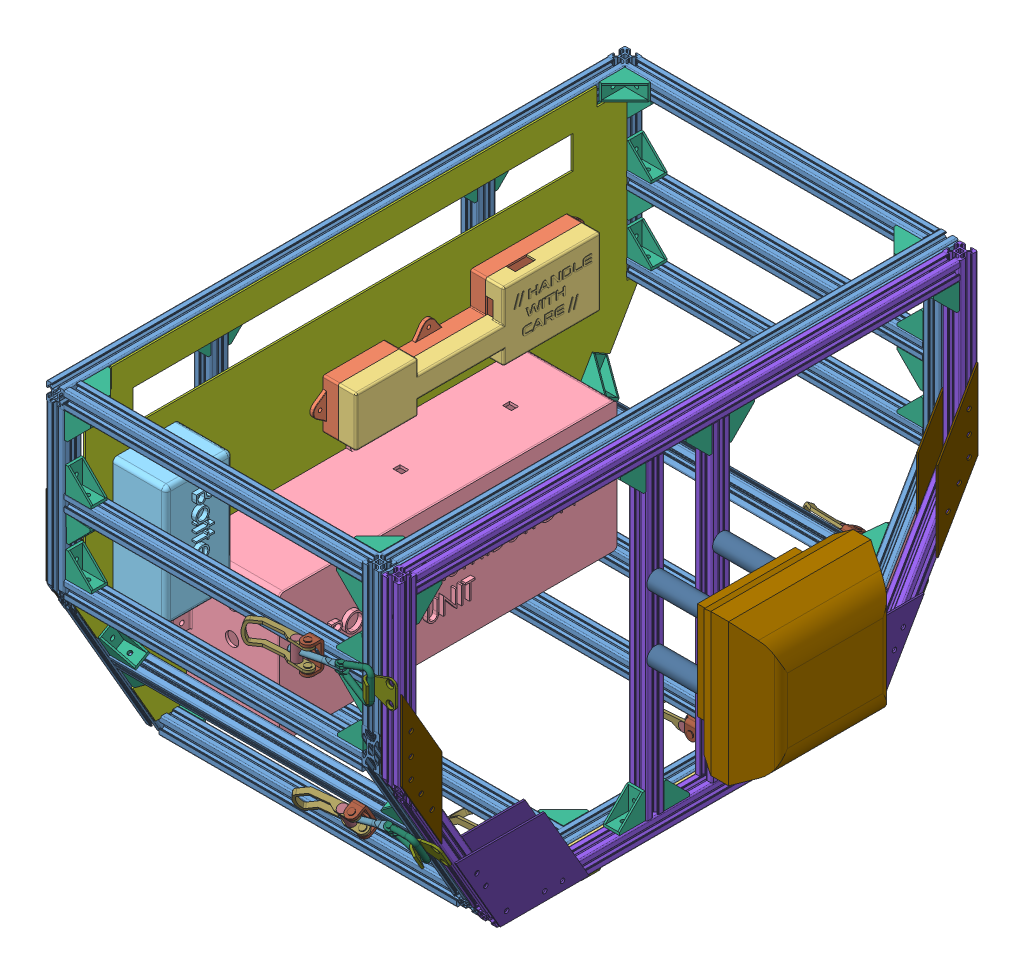
SolidWorks assembly EC, configuration Default. Lengths in mm.
Overall size (565.09 437.52 771.95).
126 component instances, 22 part files, 227 mates.
Components (placement in the parent):
- Electronics Compartment Chassis-1: Electronics Compartment Chassis [Default<As Machined>] at (390.9071 331.5 537.468) size (375 389.98 651)
- n_spartan_base-1: n_spartan_base [Default] at (47.906 291.3679 370.8745) x (0 0 -1) z (1 0 0) size (305.49 76.62 17)
- n_spartan_cover-1: n_spartan_cover [Default] at (82.906 343.2131 421.3662) x (0 0 -1) z (1 0 0) size (275.49 76.62 20.5)
- PDU Enclosure-1: PDU Enclosure [Default] at (50.906 216.04 537.5373) x (0 0 -1) z (1 0 0) size (420 186 110)
- Battery-2: Battery [Default] at (47.906 343.2622 772.8187) x (0 -1 0) z (1 0 0) size (135 75 65)
- L- Bracket-1: L- Bracket [Default] at (45.906 482.1078 853.4678) x (0 0 -1) z (-1 0 0) size (18 29 29)
- L- Bracket-2: L- Bracket [Default] at (45.906 491.6051 842.9695) x (0 1 0) z (-1 0 0) size (18 29 29)
- L- Bracket-3: L- Bracket [Default] at (36.4082 482.1065 842.9678) x (1 0 0) z (0 1 0) size (18 29 29)
- L- Bracket-4: L- Bracket [Default] at (380.9082 492.6078 842.9695) x (0 1 0) z (0 0 1) size (18 29 29)
- L- Bracket-5: L- Bracket [Default] at (390.406 482.1082 842.9695) x (1 0 0) z (0 1 0) size (18 29 29)
- L- Bracket-6: L- Bracket [Default] at (380.9082 482.1078 853.4695) x (0 0 -1) z (0 1 0) size (18 29 29)
- L- Bracket-7: L- Bracket [Default] at (45.906 482.1078 222.4695) x (0 0 -1) z (-1 0 0) size (18 29 29)
- L- Bracket-8: L- Bracket [Default] at (35.406 482.1065 231.9682) x (1 0 0) z (0 0 -1) size (18 29 29)
- L- Bracket-9: L- Bracket [Default] at (45.906 492.6065 231.9682) x (0 -1 0) z (-1 0 0) size (18 29 29)
- L- Bracket-10: L- Bracket [Default] at (380.9082 482.1078 222.4678) x (0 0 1) z (1 0 0) size (18 29 29)
- L- Bracket-11: L- Bracket [Default] at (380.9082 491.6069 231.9682) x (0 1 0) z (1 0 0) size (18 29 29)
- L- Bracket-12: L- Bracket [Default] at (391.4082 482.1082 231.9665) x (1 0 0) z (0 0 -1) size (18 29 29)
- L- Bracket-13: L- Bracket [Default] at (45.906 317.1056 852.4665) x (0 0 1) z (-1 0 0) size (18 29 29)
- L- Bracket-14: L- Bracket [Default] at (380.9082 317.1056 852.4682) x (0 0 -1) z (1 0 0) size (18 29 29)
- L- Bracket-15: L- Bracket [Default] at (380.9082 317.1056 222.4695) x (0 0 1) z (0 -1 0) size (18 29 29)
- L- Bracket-16: L- Bracket [Default] at (45.906 317.1056 222.4695) x (0 0 1) z (-1 0 0) size (18 29 29)
- L- Bracket-17: L- Bracket [Default] at (45.906 122.6252 736.1695) x (0 1 0) z (-1 0 0) size (18 29 29)
- L- Bracket-18: L- Bracket [Default] at (45.906 121.6239 338.7682) x (0 -1 0) z (-1 0 0) size (18 29 29)
- L- Bracket-20: L- Bracket [Default] at (380.9082 122.6234 338.7682) x (0 -1 0) z (0 0 -1) size (18 29 29)
- L- Bracket-21: L- Bracket [Default] at (380.9082 122.6234 736.1695) x (0 1 0) z (0 0 1) size (18 29 29)
- EC Bed-1: EC Bed [Default] at (47.906 -2.0799 1073.4615) x (0 -0.000568 1) z (-1 0 0) size (641.6 389.98 2)
- GPS Lid Assembly-1: GPS Lid Assembly [Default] at (101.4637 813.5756 803.4311) x (0 0 -1) z (-0.000003 -1 0) size (651 185.1 390)
  - GPS Lid-1: GPS Lid [Default<As Machined>] at (264.959 312.4365 321.65) size (651 20 390)
  - GPS-1: GPS [Default] at (220.0427 343.778 364.2591) size (160 165 160)
    - Electronics_GPS-1: Electronics_GPS [Default] at (45.0778 103.759 123.5701) size (160 100 160)
    - GPS_Spacer-1: GPS_Spacer [Default] at (82.0778 -21.241 160.5701) x (-0.327705 0 -0.94478) z (0 1 0) size (20 20 65)
    - GPS_Spacer-2: GPS_Spacer [Default] at (8.0778 -21.241 86.5701) x (0.991067 0 0.133362) z (0 1 0) size (20 20 65)
    - GPS_Spacer-3: GPS_Spacer [Default] at (8.0778 -21.241 160.5701) x (0.953346 0 0.301881) z (0 1 0) size (20 20 65)
    - GPS_Spacer-4: GPS_Spacer [Default] at (82.0778 -21.241 86.5701) x (0.550145 0 -0.835069) z (0 1 0) size (20 20 65)
  - L- Bracket-1: L- Bracket [Default] at (217.9605 311.9355 681.6515) x (0 -1 0) z (1 0 0) size (18 29 29)
  - L- Bracket-2: L- Bracket [Default] at (237.9592 312.9376 681.6515) x (0 1 0) z (-1 0 0) size (18 29 29)
  - L- Bracket-3: L- Bracket [Default] at (311.9592 312.9376 681.6515) x (0 1 0) z (-1 0 0) size (18 29 29)
  - L- Bracket-4: L- Bracket [Default] at (-40.5408 312.9376 331.6485) x (0 -1 0) z (-1 0 0) size (18 29 29)
  - L- Bracket-5: L- Bracket [Default] at (570.4605 312.9376 331.6485) x (0 1 0) z (1 0 0) size (18 29 29)
  - L- Bracket-6: L- Bracket [Default] at (311.9592 311.9355 331.6485) x (0 -1 0) z (-1 0 0) size (18 29 29)
  - L- Bracket-7: L- Bracket [Default] at (291.9605 312.9376 331.6485) x (0 1 0) z (1 0 0) size (18 29 29)
  - L- Bracket-8: L- Bracket [Default] at (217.9605 312.9376 331.6485) x (0 1 0) z (1 0 0) size (18 29 29)
- L- Bracket-22: L- Bracket [Default] at (45.906 213.29 276.7122) x (0 -0.5 -0.866025) z (0 -0.866025 0.5) size (18 29 29)
- L- Bracket-23: L- Bracket [Default] at (45.906 195.9711 286.7125) x (0 0.5 0.866025) z (0 0.866025 -0.5) size (18 29 29)
- L- Bracket-24: L- Bracket [Default] at (45.906 222.4898 803.5353) x (0 -0.5 0.866025) z (-1 0 0) size (18 29 29)
- L- Bracket-25: L- Bracket [Default] at (45.906 205.1704 793.536) x (0 0.5 -0.866025) z (-1 0 0) size (18 29 29)
- L- Bracket-26: L- Bracket [Default] at (45.906 122.6252 636.1695) x (0 1 0) z (-1 0 0) size (18 29 29)
- L- Bracket-27: L- Bracket [Default] at (45.906 122.6252 656.1682) x (0 -1 0) z (-1 0 0) size (18 29 29)
- ADJUSTABLE CLAMP-1: ADJUSTABLE CLAMP [LOCKED ] at (339.102 111.9247 428.703) x (0 0 -1) z (-0.000003 -1 0) size (39.54 155.02 32.17)
  - CLAMP - BRACKET-1: CLAMP - BRACKET [Default] at origin size (33.5 16 18)
  - CLAMP - HANDLE-1: CLAMP - HANDLE [Default] at origin size (25.5 70.98 19.58)
  - SWIVEL PIN-1: SWIVEL PIN [Default] at (0 -3.0558 -3.8626) x (1 0 0) z (0 0.221472 0.975167) size (25 10 10)
  - ADJUSTMENT SCREW-1: ADJUSTMENT SCREW [Default] at (0 6.7802 -6.2479) x (1 0 0) z (0 0.221472 0.975167) size (7.24 54.03 12.85)
  - LATCH-1: LATCH [Default] at (0 12.0699 -12.0483) x (1 0 0) z (0 -0.243377 0.969932) size (39.54 46.19 13.29)
  - CATCH-1: CATCH [Default] at (0 9 0) size (30 30.4 16.71)
- ADJUSTABLE CLAMP-2: ADJUSTABLE CLAMP [LOCKED ] at (339.102 111.9247 646.6324) x (0 0 -1) z (-0.000003 -1 0) size (39.54 155.02 32.17)
  - CLAMP - BRACKET-1: CLAMP - BRACKET [Default] at origin size (33.5 16 18)
  - CLAMP - HANDLE-1: CLAMP - HANDLE [Default] at origin size (25.5 70.98 19.58)
  - SWIVEL PIN-1: SWIVEL PIN [Default] at (0 -3.0558 -3.8626) x (1 0 0) z (0 0.221472 0.975167) size (25 10 10)
  - ADJUSTMENT SCREW-1: ADJUSTMENT SCREW [Default] at (0 6.7802 -6.2479) x (1 0 0) z (0 0.221472 0.975167) size (7.24 54.03 12.85)
  - LATCH-1: LATCH [Default] at (0 12.0699 -12.0483) x (1 0 0) z (0 -0.243377 0.969932) size (39.54 46.19 13.29)
  - CATCH-1: CATCH [Default] at (0 9 0) size (30 30.4 16.71)
- ADJUSTABLE CLAMP-3: ADJUSTABLE CLAMP [LOCKED ] at (339.1022 207.7726 808.2717) x (-0.000002 -0.866025 -0.5) z (-0.000001 -0.5 0.866025) size (39.54 155.02 32.17)
  - CLAMP - BRACKET-1: CLAMP - BRACKET [Default] at origin size (33.5 16 18)
  - CLAMP - HANDLE-1: CLAMP - HANDLE [Default] at origin size (25.5 70.98 19.58)
  - SWIVEL PIN-1: SWIVEL PIN [Default] at (0 -3.0558 -3.8626) x (1 0 0) z (0 0.221472 0.975167) size (25 10 10)
  - ADJUSTMENT SCREW-1: ADJUSTMENT SCREW [Default] at (0 6.7802 -6.2479) x (1 0 0) z (0 0.221472 0.975167) size (7.24 54.03 12.85)
  - LATCH-1: LATCH [Default] at (0 12.0699 -12.0483) x (1 0 0) z (0 -0.243377 0.969932) size (39.54 46.19 13.29)
  - CATCH-1: CATCH [Default] at (0 9 0) size (30 30.4 16.71)
- L- Bracket-28: L- Bracket [Default] at (45.906 122.6252 418.7695) x (0 1 0) z (-1 0 0) size (18 29 29)
- L- Bracket-29: L- Bracket [Default] at (45.906 122.6252 438.7682) x (0 -1 0) z (-1 0 0) size (18 29 29)
- L- Bracket-30: L- Bracket [Default] at (45.906 381.9702 221.4682) x (0 0 1) z (0 1 0) size (18 29 29)
- L- Bracket-31: L- Bracket [Default] at (45.906 401.9689 222.4695) x (0 0 1) z (-1 0 0) size (18 29 29)
- L- Bracket-33: L- Bracket [Default] at (48.0128 401.8743 854.7029) x (-0.002846 -0.000008 0.999996) z (-0.999992 -0.002846 -0.002847) size (18 29 29)
- L- Bracket-34: L- Bracket [Default] at (47.2341 381.8733 852.424) x (-0.070876 -0.000202 0.997485) z (-0.002847 0.999996 0) size (18 29 29)
- L- Bracket-35: L- Bracket [Default] at (380.9082 401.9689 222.4678) x (0 0 1) z (0 -1 0) size (18 29 29)
- L- Bracket-36: L- Bracket [Default] at (380.9082 381.9702 222.4678) x (0 0 -1) z (0 1 0) size (18 29 29)
- L- Bracket-37: L- Bracket [Default] at (380.9082 213.2891 276.7107) x (0 0.5 0.866025) z (0 -0.866025 0.5) size (18 29 29)
- L- Bracket-38: L- Bracket [Default] at (380.9082 195.9697 286.71) x (0 -0.5 -0.866025) z (0 0.866025 -0.5) size (18 29 29)
- L- Bracket-39: L- Bracket [Default] at (380.9082 122.6234 418.7695) x (0 1 0) z (0 0 1) size (18 29 29)
- L- Bracket-40: L- Bracket [Default] at (380.9082 122.6234 438.7682) x (0 -1 0) z (0 0 -1) size (18 29 29)
- L- Bracket-41: L- Bracket [Default] at (380.9082 122.6234 656.1682) x (0 -1 0) z (0 0 -1) size (18 29 29)
- L- Bracket-42: L- Bracket [Default] at (380.9082 122.6234 636.1695) x (0 1 0) z (0 0 1) size (18 29 29)
- L- Bracket-43: L- Bracket [Default] at (380.9082 205.1695 793.5375) x (0 0.5 -0.866025) z (0 0.866025 0.5) size (18 29 29)
- L- Bracket-44: L- Bracket [Default] at (380.9082 222.4889 803.5368) x (0 -0.5 0.866025) z (0 -0.866025 -0.5) size (18 29 29)
- L- Bracket-45: L- Bracket [Default] at (380.9082 382.851 852.453) x (0 -0.006101 0.999981) z (1 0 0) size (18 29 29)
- L- Bracket-46: L- Bracket [Default] at (380.9082 403.0563 853.4359) x (0 0.003337 -0.999994) z (1 0 0) size (18 29 29)
- ADJUSTABLE CLAMP-4: ADJUSTABLE CLAMP [LOCKED ] at (339.1022 199.1283 273.6613) x (0.000002 0.866025 -0.5) z (-0.000001 -0.5 -0.866025) size (39.54 155.02 32.17)
  - CLAMP - BRACKET-1: CLAMP - BRACKET [Default] at origin size (33.5 16 18)
  - CLAMP - HANDLE-1: CLAMP - HANDLE [Default] at origin size (25.5 70.98 19.58)
  - SWIVEL PIN-1: SWIVEL PIN [Default] at (0 -3.0558 -3.8626) x (1 0 0) z (0 0.221472 0.975167) size (25 10 10)
  - ADJUSTMENT SCREW-1: ADJUSTMENT SCREW [Default] at (0 6.7802 -6.2479) x (1 0 0) z (0 0.221472 0.975167) size (7.24 54.03 12.85)
  - LATCH-1: LATCH [Default] at (0 12.0699 -12.0483) x (1 0 0) z (0 -0.243377 0.969932) size (39.54 46.19 13.29)
  - CATCH-1: CATCH [Default] at (0 9 0) size (30 30.4 16.71)
- ADJUSTABLE CLAMP-7: ADJUSTABLE CLAMP [LOCKED ] at (339.1027 392.0581 863.9706) x (-0.000003 -1 0) z (0 0 1) size (39.54 155.02 32.17)
  - CLAMP - BRACKET-1: CLAMP - BRACKET [Default] at origin size (33.5 16 18)
  - CLAMP - HANDLE-1: CLAMP - HANDLE [Default] at origin size (25.5 70.98 19.58)
  - SWIVEL PIN-1: SWIVEL PIN [Default] at (0 -3.0558 -3.8626) x (1 0 0) z (0 0.221472 0.975167) size (25 10 10)
  - ADJUSTMENT SCREW-1: ADJUSTMENT SCREW [Default] at (0 6.7802 -6.2479) x (1 0 0) z (0 0.221472 0.975167) size (7.24 54.03 12.85)
  - LATCH-1: LATCH [Default] at (0 12.0699 -12.0483) x (1 0 0) z (0 -0.243377 0.969932) size (39.54 46.19 13.29)
  - CATCH-1: CATCH [Default] at (0 9 0) size (30 30.4 16.71)
- EC Shear Plate 1-1: EC Shear Plate 1 [Default] at (402.906 200.226 801.0756) x (0 -0.153016 -0.988224) z (-1 0 0) size (161.49 93.23 2)
- EC Shear Plate 1-2: EC Shear Plate 1 [Default] at (402.906 113.6234 423.8604) x (0 0.779319 -0.626628) z (-1 0 0) size (161.49 93.23 2)
- EC Shear Plate 2-1: EC Shear Plate 2 [Default] at (402.906 226.8868 816.4682) x (0 0.707107 0.707107) z (-1 0 0) size (150.57 86.93 2)
- EC Shear Plate 2-2: EC Shear Plate 2 [Default] at (400.906 226.8868 258.4678) x (0 0.707107 -0.707107) z (1 0 0) size (150.57 86.93 2)
- EC Shear Plate 1-3: EC Shear Plate 1 [Default] at (25.9082 113.6252 423.8614) x (0 0.779319 -0.626628) z (-1 0 0) size (161.49 93.23 2)
- EC Shear Plate 1-4: EC Shear Plate 1 [Default] at (25.9082 200.2277 801.0746) x (0 -0.153016 -0.988224) z (-1 0 0) size (161.49 93.23 2)
- EC Shear Plate 2-3: EC Shear Plate 2 [Default] at (23.9082 226.8872 258.4695) x (0 0.707107 -0.707107) z (1 0 0) size (150.57 86.93 2)
- EC Shear Plate 2-4: EC Shear Plate 2 [Default] at (23.9082 394.8295 861.4665) x (0 -0.965926 0.258819) z (1 0 0) size (150.57 86.93 2)
- EC Shear Plate 1-5: EC Shear Plate 1 [Default] at (425.8975 200.027 802.0679) x (0 -0.153016 -0.988224) z (-1 0.000003 0) size (161.49 93.23 2)
- EC Shear Plate 1-6: EC Shear Plate 1 [Default] at (425.8972 113.4245 424.8743) x (0.000002 0.779319 -0.626628) z (-1 0.000003 0) size (161.49 93.23 2)
- EC Shear Plate 2-5: EC Shear Plate 2 [Default] at (423.8975 226.7048 259.4719) x (0.000002 0.707107 -0.707107) z (1 -0.000003 0) size (150.57 86.93 2)
- EC Shear Plate 2-6: EC Shear Plate 2 [Default] at (425.8975 226.7053 817.4706) x (0.000002 0.707107 0.707107) z (-1 0.000003 0) size (150.57 86.93 2)
- EC Spacer 1-1: EC Spacer 1 [Default] at (403.906 0 1074.936) x (0 0 1) z (-1 0 0) size (648 134.82 3)
- EC Spacer 3-1: EC Spacer 3 [Default] at (400.906 -0.0558 -0.0322) x (0 0 -1) z (1 0 0) size (34.53 59.81 3)
- EC Spacer 2-1: EC Spacer 2 [Default] at (403.906 0 1075.3966) x (0 0 1) z (-1 0 0) size (244.81 17 3)
- EC Spacer 4-1: EC Spacer 4 [Default] at (436.1631 0.8411 1.5304) x (0.093475 0.00253 -0.995618) z (0.994158 0.053968 0.093475) size (34.65 60.01 3)
- L- Bracket-47: L- Bracket [Default] at (36.4093 482.1065 397.4682) x (1 0 0) z (0 0 -1) size (18 29 29)
- L- Bracket-48: L- Bracket [Default] at (36.4082 482.1065 377.4695) x (1 0 0) z (0 1 0) size (18 29 29)
- L- Bracket-49: L- Bracket [Default] at (36.4082 482.1065 677.4695) x (-1 0 0) z (0 0 1) size (18 29 29)
- L- Bracket-50: L- Bracket [Default] at (45.906 401.9689 222.4695) x (0 0 1) z (-1 0 0) size (18 29 29)
- L- Bracket-51: L- Bracket [Default] at (36.4082 482.1065 697.4682) x (1 0 0) z (0 0 -1) size (18 29 29)
- L- Bracket-52: L- Bracket [Default] at (36.4082 132.1239 377.4695) size (18 29 29)
- L- Bracket-53: L- Bracket [Default] at (36.4082 132.1239 397.4682) x (-1 0 0) z (0 0 -1) size (18 29 29)
- L- Bracket-54: L- Bracket [Default] at (36.4082 132.1239 677.4695) size (18 29 29)
- L- Bracket-55: L- Bracket [Default] at (36.4082 132.1239 697.4682) x (-1 0 0) z (0 0 -1) size (18 29 29)
Mates (geometry in assembly coordinates):
- Coincident183: coincident: plane of Electronics Compartment Chassis-1 through (47.906 331.5 537.468) normal (1 0 0); plane of n_spartan_base-1 through (47.906 291.3679 370.8745) normal (-1 0 0)
- Lock9: lock: unknown of Electronics Compartment Chassis-1; unknown of n_spartan_base-1
- Coincident185: coincident: line of n_spartan_base-1 through (64.906 391.3411 298.0369) axis (0 -1 0); line of n_spartan_cover-1 through (64.906 318.7182 298.0369) axis (0 1 0)
- Coincident186: coincident: line of n_spartan_base-1 through (64.906 332.8683 408.5193) axis (0 0 1); line of n_spartan_cover-1 through (64.906 332.8683 502.5227) axis (0 0 -1)
- Coincident187: coincident: plane of Electronics Compartment Chassis-1 through (47.906 331.5 537.468) normal (1 0 0); plane of PDU Enclosure-1 through (47.906 216.04 537.5373) normal (-1 0 0)
- Lock12: lock: unknown of Electronics Compartment Chassis-1; unknown of PDU Enclosure-1
- Coincident192: coincident: plane of Electronics Compartment Chassis-1 through (47.906 331.5 537.468) normal (1 0 0); plane of Battery-2 through (47.906 343.2622 772.8187) normal (-1 0 0)
- Parallel7: parallel: line of Electronics Compartment Chassis-1 through (47.906 480.6069 861.4682) axis (0 -1 0); line of Battery-2 through (47.906 405.7622 810.3187) axis (0 -1 0)
- Coincident280389272: coincident: plane of Electronics Compartment Chassis-1 through (45.906 307.1067 856.7169) normal (1 0 0); plane of L- Bracket-1 through (45.906 453.1078 862.4678) normal (-1 0 0)
- Coincident280389273: coincident: plane of Electronics Compartment Chassis-1 through (35.9071 482.1078 856.7169) normal (0 -1 0); plane of L- Bracket-1 through (45.906 482.1078 862.4678) normal (0 1 0)
- Coincident280389274: coincident: line of Electronics Compartment Chassis-1 through (45.906 272.3869 844.4678) axis (0 1 0); line of L- Bracket-1 through (45.906 453.1078 844.4678) axis (0 1 0)
- Coincident280389275: coincident: plane of Electronics Compartment Chassis-1 through (45.906 495.8556 852.968) normal (1 0 0); plane of L- Bracket-2 through (45.906 482.6051 813.9695) normal (-1 0 0)
- Coincident280389276: coincident: plane of Electronics Compartment Chassis-1 through (35.9071 500.6056 842.9695) normal (0 0 -1); plane of L- Bracket-2 through (45.906 482.6051 842.9695) normal (0 0 1)
- Coincident280389277: coincident: line of Electronics Compartment Chassis-1 through (45.906 500.6051 862.9665) axis (0 0 -1); line of L- Bracket-2 through (45.906 500.6051 813.9695) axis (0 0 1)
- Coincident280389278: coincident: plane of Electronics Compartment Chassis-1 through (27.4082 482.1065 852.968) normal (0 -1 0); plane of L- Bracket-3 through (27.4082 482.1065 813.9678) normal (0 1 0)
- Coincident280389279: coincident: plane of Electronics Compartment Chassis-1 through (39.656 307.1067 842.9678) normal (0 0 -1); plane of L- Bracket-3 through (27.4082 482.1065 842.9678) normal (0 0 1)
- Coincident280389280: coincident: line of Electronics Compartment Chassis-1 through (27.4082 269.7889 842.9678) axis (0 1 0); line of L- Bracket-3 through (27.4082 482.1065 842.9678) axis (0 -1 0)
- Coincident280389281: coincident: plane of Electronics Compartment Chassis-1 through (380.9082 495.8556 221.968) normal (-1 0 0); plane of L- Bracket-4 through (380.9082 483.6078 842.9695) normal (1 0 0)
- Coincident280389282: coincident: plane of Electronics Compartment Chassis-1 through (35.9071 500.6056 842.9695) normal (0 0 -1); plane of L- Bracket-4 through (351.9082 483.6078 842.9695) normal (0 0 1)
- Coincident280389283: coincident: line of Electronics Compartment Chassis-1 through (45.906 483.6078 842.9695) axis (1 0 0); line of L- Bracket-4 through (351.9082 483.6078 842.9695) axis (1 0 0)
- Coincident280389284: coincident: plane of Electronics Compartment Chassis-1 through (399.406 492.1067 842.9695) normal (0 0 -1); plane of L- Bracket-5 through (381.406 482.1082 842.9695) normal (0 0 1)
- Coincident280389285: coincident: plane of Electronics Compartment Chassis-1 through (399.406 482.1082 221.968) normal (0 -1 0); plane of L- Bracket-5 through (381.406 482.1082 813.9695) normal (0 1 0)
- Coincident280389286: coincident: line of Electronics Compartment Chassis-1 through (399.406 502.1069 842.9695) axis (0 -1 0); line of L- Bracket-5 through (399.406 482.1082 842.9695) axis (0 -1 0)
- Coincident280389287: coincident: plane of Electronics Compartment Chassis-1 through (35.9071 482.1078 844.4695) normal (0 -1 0); plane of L- Bracket-6 through (351.9082 482.1078 862.4695) normal (0 1 0)
- Coincident280389288: coincident: plane of Electronics Compartment Chassis-1 through (380.9082 492.1067 856.7169) normal (-1 0 0); plane of L- Bracket-6 through (380.9082 482.1078 862.4695) normal (1 0 0)
- Coincident280389289: coincident: line of Electronics Compartment Chassis-1 through (380.9082 502.1069 844.4695) axis (0 -1 0); line of L- Bracket-6 through (380.9082 482.1078 844.4695) axis (0 -1 0)
- Coincident280389290: coincident: plane of Electronics Compartment Chassis-1 through (35.9071 482.1078 213.4695) normal (0 -1 0); plane of L- Bracket-7 through (45.906 482.1078 231.4695) normal (0 1 0)
- Coincident280389291: coincident: plane of Electronics Compartment Chassis-1 through (45.906 492.1067 218.2191) normal (1 0 0); plane of L- Bracket-7 through (45.906 453.1078 231.4695) normal (-1 0 0)
- Coincident280389292: coincident: line of Electronics Compartment Chassis-1 through (45.906 502.1051 213.4695) axis (0 -1 0); line of L- Bracket-7 through (45.906 453.1078 213.4695) axis (0 1 0)
- Coincident280389293: coincident: plane of Electronics Compartment Chassis-1 through (39.656 482.1065 852.968) normal (0 -1 0); plane of L- Bracket-8 through (26.406 482.1065 231.9682) normal (0 1 0)
- Coincident280389294: coincident: plane of Electronics Compartment Chassis-1 through (27.4082 492.1067 231.9682) normal (0 0 1); plane of L- Bracket-8 through (26.406 453.1065 231.9682) normal (0 0 -1)
- Coincident280389295: coincident: line of Electronics Compartment Chassis-1 through (44.406 482.1065 862.9665) axis (0 0 -1); line of L- Bracket-8 through (44.406 482.1065 231.9682) axis (0 0 1)
- Coincident280389296: coincident: plane of Electronics Compartment Chassis-1 through (35.9071 495.8556 231.9682) normal (0 0 1); plane of L- Bracket-9 through (45.906 501.6065 231.9682) normal (0 0 -1)
- Coincident280389297: coincident: plane of Electronics Compartment Chassis-1 through (45.906 495.8556 852.968) normal (1 0 0); plane of L- Bracket-9 through (45.906 501.6065 260.9682) normal (-1 0 0)
- Coincident280389298: coincident: line of Electronics Compartment Chassis-1 through (45.906 483.6065 862.9665) axis (0 0 -1); line of L- Bracket-9 through (45.906 483.6065 260.9682) axis (0 0 -1)
- Coincident280389299: coincident: plane of Electronics Compartment Chassis-1 through (380.9082 307.1067 230.4665) normal (-1 0 0); plane of L- Bracket-10 through (380.9082 453.1078 213.4678) normal (1 0 0)
- Coincident280389300: coincident: plane of Electronics Compartment Chassis-1 through (35.9071 482.1078 213.4695) normal (0 -1 0); plane of L- Bracket-10 through (380.9082 482.1078 213.4678) normal (0 1 0)
- Coincident280389301: coincident: line of Electronics Compartment Chassis-1 through (380.9082 301.8291 213.4678) axis (0 1 0); line of L- Bracket-10 through (380.9082 453.1078 213.4678) axis (0 1 0)
- Coincident280389302: coincident: plane of Electronics Compartment Chassis-1 through (380.9082 483.6082 221.968) normal (-1 0 0); plane of L- Bracket-11 through (380.9082 482.6069 260.9682) normal (1 0 0)
- Coincident280389303: coincident: plane of Electronics Compartment Chassis-1 through (35.9071 495.8556 231.9682) normal (0 0 1); plane of L- Bracket-11 through (380.9082 482.6069 231.9682) normal (0 0 -1)
- Coincident280389304: coincident: line of Electronics Compartment Chassis-1 through (380.9082 500.6069 211.9678) axis (0 0 1); line of L- Bracket-11 through (380.9082 500.6069 260.9682) axis (0 0 -1)
- Coincident280389305: coincident: plane of Electronics Compartment Chassis-1 through (399.406 482.1082 221.968) normal (0 -1 0); plane of L- Bracket-12 through (382.4082 482.1082 231.9665) normal (0 1 0)
- Coincident280389306: coincident: plane of Electronics Compartment Chassis-1 through (387.1582 307.1067 231.9665) normal (0 0 1); plane of L- Bracket-12 through (382.4082 453.1082 231.9665) normal (0 0 -1)
- Coincident280389307: coincident: line of Electronics Compartment Chassis-1 through (382.4082 269.7884 231.9665) axis (0 1 0); line of L- Bracket-12 through (382.4082 453.1082 231.9665) axis (0 1 0)
- Coincident280389308: coincident: plane of Electronics Compartment Chassis-1 through (35.9071 317.1056 861.4682) normal (0 1 0); plane of L- Bracket-13 through (45.906 317.1056 843.4665) normal (0 -1 0)
- Coincident280389309: coincident: plane of Electronics Compartment Chassis-1 through (45.906 307.1067 856.7169) normal (1 0 0); plane of L- Bracket-13 through (45.906 346.1056 843.4665) normal (-1 0 0)
- Coincident280389310: coincident: line of Electronics Compartment Chassis-1 through (45.906 301.8295 861.4665) axis (0 1 0); line of L- Bracket-13 through (45.906 346.1056 861.4665) axis (0 -1 0)
- Coincident280389311: coincident: plane of L- Bracket-14 through (380.9082 346.1056 861.4682) normal (1 0 0); plane of Electronics Compartment Chassis-1 through (380.9082 492.1067 856.7169) normal (-1 0 0)
- Coincident280389312: coincident: line of Electronics Compartment Chassis-1 through (45.906 317.1056 861.4682) axis (1 0 0); line of L- Bracket-14 through (380.9082 317.1056 861.4682) axis (-1 0 0)
- Coincident280389313: coincident: plane of Electronics Compartment Chassis-1 through (35.9071 317.1056 230.4682) normal (0 1 0); plane of L- Bracket-15 through (351.9082 317.1056 213.4695) normal (0 -1 0)
- Coincident280389314: coincident: plane of Electronics Compartment Chassis-1 through (380.9082 307.1067 218.2191) normal (-1 0 0); plane of L- Bracket-15 through (380.9082 317.1056 213.4695) normal (1 0 0)
- Coincident280389315: coincident: line of Electronics Compartment Chassis-1 through (45.906 317.1056 213.4695) axis (1 0 0); line of L- Bracket-15 through (351.9082 317.1056 213.4695) axis (1 0 0)
- Coincident280389316: coincident: plane of Electronics Compartment Chassis-1 through (35.9071 317.1056 218.2191) normal (0 1 0); plane of L- Bracket-16 through (45.906 317.1056 213.4695) normal (0 -1 0)
- Coincident280389317: coincident: plane of Electronics Compartment Chassis-1 through (45.906 492.1067 230.4682) normal (1 0 0); plane of L- Bracket-16 through (45.906 346.1056 213.4695) normal (-1 0 0)
- Coincident280389318: coincident: line of Electronics Compartment Chassis-1 through (45.906 502.1051 213.4695) axis (0 -1 0); line of L- Bracket-16 through (45.906 346.1056 213.4695) axis (0 -1 0)
- Coincident280389319: coincident: plane of Electronics Compartment Chassis-1 through (45.906 118.3747 328.768) normal (1 0 0); plane of L- Bracket-17 through (45.906 113.6252 707.1695) normal (-1 0 0)
- Coincident280389320: coincident: plane of Electronics Compartment Chassis-1 through (35.9071 130.6226 736.1695) normal (0 0 -1); plane of L- Bracket-17 through (45.906 113.6252 736.1695) normal (0 0 1)
- Coincident280389321: coincident: line of Electronics Compartment Chassis-1 through (45.906 113.6252 322.1294) axis (0 0 1); line of L- Bracket-17 through (45.906 113.6252 707.1695) axis (0 0 1)
- Coincident280389322: coincident: plane of Electronics Compartment Chassis-1 through (45.906 130.6239 328.768) normal (1 0 0); plane of L- Bracket-18 through (45.906 130.6239 367.7682) normal (-1 0 0)
- Coincident280389323: coincident: plane of Electronics Compartment Chassis-1 through (35.9071 113.6248 338.7682) normal (0 0 1); plane of L- Bracket-18 through (45.906 130.6239 338.7682) normal (0 0 -1)
- Coincident280389324: coincident: line of Electronics Compartment Chassis-1 through (45.906 130.6239 312.3152) axis (0 0 1); line of L- Bracket-18 through (45.906 130.6239 367.7682) axis (0 0 -1)
- Coincident280389328: coincident: plane of Electronics Compartment Chassis-1 through (35.9071 125.8726 338.7682) normal (0 0 1); plane of L- Bracket-20 through (351.9082 131.6234 338.7682) normal (0 0 -1)
- Coincident280389329: coincident: plane of Electronics Compartment Chassis-1 through (380.9082 130.6221 746.168) normal (-1 0 0); plane of L- Bracket-20 through (380.9082 131.6234 338.7682) normal (1 0 0)
- Coincident280389330: coincident: line of Electronics Compartment Chassis-1 through (380.9082 113.6234 752.8077) axis (0 0 -1); line of L- Bracket-20 through (380.9082 113.6234 338.7682) axis (0 0 1)
- Coincident280389331: coincident: plane of Electronics Compartment Chassis-1 through (380.9082 130.6221 746.168) normal (-1 0 0); plane of L- Bracket-21 through (380.9082 113.6234 736.1695) normal (1 0 0)
- Coincident280389332: coincident: plane of Electronics Compartment Chassis-1 through (35.9071 118.3747 736.1695) normal (0 0 -1); plane of L- Bracket-21 through (351.9082 113.6234 736.1695) normal (0 0 1)
- Coincident280389333: coincident: line of Electronics Compartment Chassis-1 through (380.9082 113.6234 752.8077) axis (0 0 -1); line of L- Bracket-21 through (380.9082 113.6234 736.1695) axis (0 0 -1)
- Coincident280389334: coincident: plane of Electronics Compartment Chassis-1 through (45.906 495.8556 852.968) normal (1 0 0); plane of EC Bed-1 through (45.906 -2.0799 1073.4615) normal (-1 0 0)
- Lock21: lock: unknown of Electronics Compartment Chassis-1; unknown of EC Bed-1
- Coincident280389336: coincident: plane of Electronics Compartment Chassis-1 through (45.906 305.2322 218.7213) normal (1 0 0); plane of L- Bracket-22 through (45.906 217.79 284.5064) normal (-1 0 0)
- Coincident280389337: coincident: plane of Electronics Compartment Chassis-1 through (45.906 211.1655 273.0325) normal (0 0.866025 -0.5); plane of L- Bracket-22 through (74.906 217.79 284.5064) normal (0 -0.866025 0.5)
- Coincident280389338: coincident: line of Electronics Compartment Chassis-1 through (45.906 307.4276 211.9695) axis (0 -0.866025 0.5); line of L- Bracket-22 through (45.906 208.79 268.918) axis (0 0.866025 -0.5)
- Coincident280389339: coincident: plane of Electronics Compartment Chassis-1 through (45.906 197.5951 289.5252) normal (0 -0.866025 0.5); plane of L- Bracket-23 through (74.906 191.4711 278.9183) normal (0 0.866025 -0.5)
- Coincident280389340: coincident: plane of Electronics Compartment Chassis-1 through (45.906 305.2322 218.7213) normal (1 0 0); plane of L- Bracket-23 through (45.906 191.4711 278.9183) normal (-1 0 0)
- Coincident280389341: coincident: line of Electronics Compartment Chassis-1 through (45.906 191.4711 278.9183) axis (1 0 0); line of L- Bracket-23 through (74.906 191.4711 278.9183) axis (-1 0 0)
- Coincident280389342: coincident: plane of Electronics Compartment Chassis-1 through (380.9082 220.3653 807.215) normal (0 0.866025 0.5); plane of L- Bracket-24 through (45.906 226.9898 795.7411) normal (0 -0.866025 -0.5)
- Coincident280389343: coincident: plane of Electronics Compartment Chassis-1 through (45.906 120.2492 749.4147) normal (1 0 0); plane of L- Bracket-24 through (45.906 252.1045 810.2411) normal (-1 0 0)
- Coincident280389344: coincident: line of Electronics Compartment Chassis-1 through (45.906 112.1252 750.2086) axis (0 0.866025 0.5); line of L- Bracket-24 through (45.906 243.1045 825.8295) axis (0 -0.866025 -0.5)
- Coincident280389345: coincident: plane of Electronics Compartment Chassis-1 through (380.9082 200.671 801.3292) normal (0 -0.866025 -0.5); plane of L- Bracket-25 through (45.906 200.6704 801.3302) normal (0 0.866025 0.5)
- Coincident280389346: coincident: plane of Electronics Compartment Chassis-1 through (45.906 120.2492 749.4147) normal (1 0 0); plane of L- Bracket-25 through (45.906 175.5557 786.8302) normal (-1 0 0)
- Coincident280389347: coincident: line of Electronics Compartment Chassis-1 through (45.906 112.1252 750.2086) axis (0 0.866025 0.5); line of L- Bracket-25 through (45.906 175.5557 786.8302) axis (0 0.866025 0.5)
- Coincident280389348: coincident: plane of Electronics Compartment Chassis-1 through (382.4082 113.6263 636.1695) normal (0 0 -1); plane of L- Bracket-26 through (45.906 113.6252 636.1695) normal (0 0 1)
- Coincident280389349: coincident: plane of Electronics Compartment Chassis-1 through (45.906 118.3747 328.768) normal (1 0 0); plane of L- Bracket-26 through (45.906 113.6252 607.1695) normal (-1 0 0)
- Coincident280389350: coincident: line of Electronics Compartment Chassis-1 through (45.906 113.6252 322.1294) axis (0 0 1); line of L- Bracket-26 through (45.906 113.6252 607.1695) axis (0 0 1)
- Coincident280389351: coincident: plane of Electronics Compartment Chassis-1 through (382.4082 118.3763 656.1682) normal (0 0 1); plane of L- Bracket-27 through (45.906 131.6252 656.1682) normal (0 0 -1)
- Coincident280389352: coincident: plane of Electronics Compartment Chassis-1 through (45.906 130.6239 328.768) normal (1 0 0); plane of L- Bracket-27 through (45.906 131.6252 685.1682) normal (-1 0 0)
- Coincident280389353: coincident: line of Electronics Compartment Chassis-1 through (45.906 113.6252 322.1294) axis (0 0 1); line of L- Bracket-27 through (45.906 113.6252 685.1682) axis (0 0 -1)
- Coincident280389354: coincident: plane of GPS Lid Assembly-1/GPS Lid-1 through (417.6472 111.9245 747.1623) normal (-0.000003 -1 0); plane of ADJUSTABLE CLAMP-1/CATCH-1 through (401.4929 111.9246 428.8029) normal (0.000003 1 0)
- Coincident280389356: coincident: line of GPS Lid Assembly-1/GPS Lid-1 through (422.3972 111.9245 752.9339) axis (0 0 -1); line of ADJUSTABLE CLAMP-1/CATCH-1 through (422.3972 111.9245 437.3029) axis (0 0 -1)
- Lock22: lock: unknown of Electronics Compartment Chassis-1; unknown of GPS Lid Assembly-1/GPS Lid-1
- Coincident280389358: coincident: plane of GPS Lid Assembly-1/GPS Lid-1 through (417.6472 111.9245 747.1623) normal (-0.000003 -1 0); plane of ADJUSTABLE CLAMP-2/CATCH-1 through (401.4929 111.9246 646.7323) normal (0.000003 1 0)
- Coincident280389359: coincident: line of GPS Lid Assembly-1/GPS Lid-1 through (422.3972 111.9245 752.9339) axis (0 0 -1); line of ADJUSTABLE CLAMP-2/CATCH-1 through (422.3972 111.9245 655.2323) axis (0 0 -1)
- Lock24: lock: unknown of Electronics Compartment Chassis-1; unknown of ADJUSTABLE CLAMP-1/CATCH-1
- Coincident280389360: coincident: plane of GPS Lid Assembly-1/GPS Lid-1 through (422.3972 116.9255 755.8213) normal (-0.000001 -0.5 0.866025); plane of ADJUSTABLE CLAMP-3/CATCH-1 through (401.4931 207.8589 808.3217) normal (0.000001 0.5 -0.866025)
- Coincident280389361: coincident: line of GPS Lid Assembly-1/GPS Lid-1 through (422.3973 131.9232 764.4802) axis (0.000002 0.866025 0.5); line of ADJUSTABLE CLAMP-3/CATCH-1 through (422.3975 215.2201 812.5717) axis (-0.000002 -0.866025 -0.5)
- Lock25: lock: unknown of Electronics Compartment Chassis-1; unknown of ADJUSTABLE CLAMP-3/CATCH-1
- Coincident280389362: coincident: plane of Electronics Compartment Chassis-1 through (382.4082 113.6263 418.7695) normal (0 0 -1); plane of L- Bracket-28 through (45.906 113.6252 418.7695) normal (0 0 1)
- Coincident280389363: coincident: plane of Electronics Compartment Chassis-1 through (45.906 118.3747 328.768) normal (1 0 0); plane of L- Bracket-28 through (45.906 113.6252 389.7695) normal (-1 0 0)
- Coincident280389364: coincident: line of Electronics Compartment Chassis-1 through (45.906 113.6252 322.1294) axis (0 0 1); line of L- Bracket-28 through (45.906 113.6252 389.7695) axis (0 0 1)
- Coincident280389365: coincident: plane of Electronics Compartment Chassis-1 through (382.4082 118.3763 438.7682) normal (0 0 1); plane of L- Bracket-29 through (45.906 131.6252 438.7682) normal (0 0 -1)
- Coincident280389366: coincident: plane of Electronics Compartment Chassis-1 through (45.906 118.3747 328.768) normal (1 0 0); plane of L- Bracket-29 through (45.906 131.6252 467.7682) normal (-1 0 0)
- Coincident280389367: coincident: line of Electronics Compartment Chassis-1 through (45.906 113.6252 322.1294) axis (0 0 1); line of L- Bracket-29 through (45.906 113.6252 467.7682) axis (0 0 -1)
- Coincident280389368: coincident: plane of Electronics Compartment Chassis-1 through (45.906 381.9702 213.4706) normal (0 -1 0); plane of L- Bracket-30 through (74.906 381.9702 212.4682) normal (0 1 0)
- Coincident280389369: coincident: plane of Electronics Compartment Chassis-1 through (45.906 492.1067 230.4682) normal (1 0 0); plane of L- Bracket-30 through (45.906 381.9702 212.4682) normal (-1 0 0)
- Coincident280389370: coincident: line of Electronics Compartment Chassis-1 through (45.906 502.1051 230.4682) axis (0 -1 0); line of L- Bracket-30 through (45.906 381.9702 230.4682) axis (0 -1 0)
- Coincident280389371: coincident: plane of Electronics Compartment Chassis-1 through (45.906 492.1067 218.2191) normal (1 0 0); plane of L- Bracket-31 through (45.906 430.9689 213.4695) normal (-1 0 0)
- Coincident280389372: coincident: plane of Electronics Compartment Chassis-1 through (45.906 401.9689 218.2206) normal (0 1 0); plane of L- Bracket-31 through (45.906 401.9689 213.4695) normal (0 -1 0)
- Coincident280389373: coincident: line of Electronics Compartment Chassis-1 through (45.906 502.1051 213.4695) axis (0 -1 0); line of L- Bracket-31 through (45.906 430.9689 213.4695) axis (0 -1 0)
- Coincident280389379: coincident: plane of Electronics Compartment Chassis-1 through (380.8797 402.8218 844.4676) normal (-0.002847 0.999996 0); plane of L- Bracket-33 through (48.0384 401.8744 845.7029) normal (0.002847 -0.999996 0)
- Lock26: lock: unknown of Electronics Compartment Chassis-1; unknown of L- Bracket-33
- Coincident280389385: coincident: plane of Electronics Compartment Chassis-1 through (380.9367 382.8232 849.2175) normal (0.002847 -0.999996 0); plane of L- Bracket-34 through (76.7989 381.9575 845.5021) normal (-0.002847 0.999996 0)
- Lock27: lock: unknown of Electronics Compartment Chassis-1; unknown of L- Bracket-34
- Coincident280389386: coincident: plane of Electronics Compartment Chassis-1 through (45.906 401.9689 218.2206) normal (0 1 0); plane of L- Bracket-35 through (351.9082 401.9689 213.4678) normal (0 -1 0)
- Coincident280389387: coincident: plane of Electronics Compartment Chassis-1 through (380.9082 307.1067 218.2191) normal (-1 0 0); plane of L- Bracket-35 through (380.9082 401.9689 213.4678) normal (1 0 0)
- Coincident280389388: coincident: line of Electronics Compartment Chassis-1 through (380.9082 301.8291 213.4678) axis (0 1 0); line of L- Bracket-35 through (380.9082 401.9689 213.4678) axis (0 1 0)
- Coincident280389389: coincident: plane of Electronics Compartment Chassis-1 through (45.906 381.9702 225.7185) normal (0 -1 0); plane of L- Bracket-36 through (351.9082 381.9702 231.4678) normal (0 1 0)
- Coincident280389390: coincident: plane of Electronics Compartment Chassis-1 through (380.9082 307.1067 230.4665) normal (-1 0 0); plane of L- Bracket-36 through (380.9082 381.9702 231.4678) normal (1 0 0)
- Coincident280389391: coincident: line of Electronics Compartment Chassis-1 through (380.9082 301.8291 213.4678) axis (0 1 0); line of L- Bracket-36 through (380.9082 381.9702 213.4678) axis (0 -1 0)
- Coincident280389392: coincident: plane of Electronics Compartment Chassis-1 through (45.906 211.1655 273.0325) normal (0 0.866025 -0.5); plane of L- Bracket-37 through (351.9082 208.7891 268.9165) normal (0 -0.866025 0.5)
- Coincident280389393: coincident: plane of Electronics Compartment Chassis-1 through (380.9082 120.2492 325.5213) normal (-1 0 0); plane of L- Bracket-37 through (380.9082 208.7891 268.9165) normal (1 0 0)
- Coincident280389394: coincident: line of Electronics Compartment Chassis-1 through (380.9082 112.1234 324.7264) axis (0 0.866025 -0.5); line of L- Bracket-37 through (380.9082 208.7891 268.9165) axis (0 0.866025 -0.5)
- Coincident280389395: coincident: plane of Electronics Compartment Chassis-1 through (45.906 191.4711 278.9183) normal (0 -0.866025 0.5); plane of L- Bracket-38 through (351.9082 200.4697 294.5043) normal (0 0.866025 -0.5)
- Coincident280389396: coincident: plane of Electronics Compartment Chassis-1 through (380.9082 126.3729 336.1279) normal (-1 0 0); plane of L- Bracket-38 through (380.9082 200.4697 294.5043) normal (1 0 0)
- Coincident280389397: coincident: line of Electronics Compartment Chassis-1 through (380.9082 112.1234 324.7264) axis (0 0.866025 -0.5); line of L- Bracket-38 through (380.9082 191.4697 278.9158) axis (0 -0.866025 0.5)
- Coincident280389398: coincident: plane of Electronics Compartment Chassis-1 through (382.4082 125.8741 418.7695) normal (0 0 -1); plane of L- Bracket-39 through (351.9082 113.6234 418.7695) normal (0 0 1)
- Coincident280389399: coincident: plane of Electronics Compartment Chassis-1 through (380.9082 118.3747 746.168) normal (-1 0 0); plane of L- Bracket-39 through (380.9082 113.6234 418.7695) normal (1 0 0)
- Coincident280389400: coincident: line of Electronics Compartment Chassis-1 through (380.9082 113.6234 752.8077) axis (0 0 -1); line of L- Bracket-39 through (380.9082 113.6234 418.7695) axis (0 0 -1)
- Coincident280389401: coincident: plane of Electronics Compartment Chassis-1 through (382.4082 130.6241 438.7682) normal (0 0 1); plane of L- Bracket-40 through (351.9082 131.6234 438.7682) normal (0 0 -1)
- Coincident280389402: coincident: plane of Electronics Compartment Chassis-1 through (380.9082 118.3747 746.168) normal (-1 0 0); plane of L- Bracket-40 through (380.9082 131.6234 438.7682) normal (1 0 0)
- Coincident280389403: coincident: line of Electronics Compartment Chassis-1 through (380.9082 113.6234 752.8077) axis (0 0 -1); line of L- Bracket-40 through (380.9082 113.6234 438.7682) axis (0 0 1)
- Coincident280389404: coincident: plane of Electronics Compartment Chassis-1 through (382.4082 130.6241 656.1682) normal (0 0 1); plane of L- Bracket-41 through (351.9082 131.6234 656.1682) normal (0 0 -1)
- Coincident280389405: coincident: plane of Electronics Compartment Chassis-1 through (380.9082 118.3747 746.168) normal (-1 0 0); plane of L- Bracket-41 through (380.9082 131.6234 656.1682) normal (1 0 0)
- Coincident280389406: coincident: line of Electronics Compartment Chassis-1 through (380.9082 113.6234 752.8077) axis (0 0 -1); line of L- Bracket-41 through (380.9082 113.6234 656.1682) axis (0 0 1)
- Coincident280389407: coincident: plane of Electronics Compartment Chassis-1 through (382.4082 113.6263 636.1695) normal (0 0 -1); plane of L- Bracket-42 through (351.9082 113.6234 636.1695) normal (0 0 1)
- Coincident280389408: coincident: plane of Electronics Compartment Chassis-1 through (380.9082 130.6221 746.168) normal (-1 0 0); plane of L- Bracket-42 through (380.9082 113.6234 636.1695) normal (1 0 0)
- Coincident280389409: coincident: line of Electronics Compartment Chassis-1 through (380.9082 113.6234 752.8077) axis (0 0 -1); line of L- Bracket-42 through (380.9082 113.6234 636.1695) axis (0 0 -1)
- Coincident280389410: coincident: plane of Electronics Compartment Chassis-1 through (380.9082 200.671 801.3292) normal (0 -0.866025 -0.5); plane of L- Bracket-43 through (351.9082 200.6695 801.3317) normal (0 0.866025 0.5)
- Coincident280389411: coincident: plane of Electronics Compartment Chassis-1 through (380.9082 305.2322 856.2147) normal (-1 0 0); plane of L- Bracket-43 through (380.9082 200.6695 801.3317) normal (1 0 0)
- Coincident280389412: coincident: line of Electronics Compartment Chassis-1 through (380.9082 307.4271 862.9682) axis (0 -0.866025 -0.5); line of L- Bracket-43 through (380.9082 200.6695 801.3317) axis (0 -0.866025 -0.5)
- Coincident280389413: coincident: plane of Electronics Compartment Chassis-1 through (380.9082 220.3653 807.215) normal (0 0.866025 0.5); plane of L- Bracket-44 through (351.9082 226.9889 795.7426) normal (0 -0.866025 -0.5)
- Coincident280389414: coincident: plane of Electronics Compartment Chassis-1 through (380.9082 311.3559 845.6081) normal (-1 0 0); plane of L- Bracket-44 through (380.9082 226.9889 795.7426) normal (1 0 0)
- Coincident280389415: coincident: line of Electronics Compartment Chassis-1 through (380.9082 307.4271 862.9682) axis (0 -0.866025 -0.5); line of L- Bracket-44 through (380.9082 217.9889 811.331) axis (0 0.866025 0.5)
- Coincident280389416: coincident: plane of Electronics Compartment Chassis-1 through (380.9082 492.1067 856.7169) normal (-1 0 0); plane of L- Bracket-45 through (380.9082 353.9064 843.2763) normal (1 0 0)
- Lock28: lock: unknown of Electronics Compartment Chassis-1; unknown of L- Bracket-45
- Coincident280389420: coincident: plane of Electronics Compartment Chassis-1 through (380.9082 492.1067 856.7169) normal (-1 0 0); plane of L- Bracket-46 through (380.9082 432.0261 862.5326) normal (1 0 0)
- Lock29: lock: unknown of Electronics Compartment Chassis-1; unknown of L- Bracket-46
- Coincident280389425: coincident: plane of GPS Lid Assembly-1/GPS Lid-1 through (417.6472 116.9246 321.1215) normal (-0.000001 -0.5 -0.866025); plane of ADJUSTABLE CLAMP-4/CATCH-1 through (401.4931 199.0417 273.7112) normal (0.000001 0.5 0.866025)
- Coincident280389426: coincident: line of GPS Lid Assembly-1/GPS Lid-1 through (422.3973 131.9232 312.4621) axis (0.000002 0.866025 -0.5); line of ADJUSTABLE CLAMP-4/CATCH-1 through (422.3974 191.6804 277.9612) axis (0.000002 0.866025 -0.5)
- Lock30: lock: unknown of Electronics Compartment Chassis-1; unknown of ADJUSTABLE CLAMP-4/CATCH-1
- Coincident280389436: coincident: plane of GPS Lid Assembly-1/GPS Lid-1 through (422.3978 306.9247 863.9706) normal (0 0 1); plane of ADJUSTABLE CLAMP-7/CATCH-1 through (401.4936 392.1578 863.9706) normal (0 0 -1)
- Coincident280389437: coincident: line of GPS Lid Assembly-1/GPS Lid-1 through (422.3978 304.2456 863.9706) axis (0.000003 1 0); line of ADJUSTABLE CLAMP-7/CATCH-1 through (422.398 400.6577 863.9706) axis (-0.000003 -1 0)
- Lock32: lock: unknown of Electronics Compartment Chassis-1; unknown of ADJUSTABLE CLAMP-7/CATCH-1
- Lock33: lock: unknown of GPS Lid Assembly-1/GPS Lid-1; unknown of ADJUSTABLE CLAMP-2/CATCH-1
- Coincident280389438: coincident: plane of Electronics Compartment Chassis-1 through (400.906 302.8566 860.3294) normal (1 0 0); plane of EC Shear Plate 1-1 through (400.906 200.226 801.0756) normal (-1 0 0)
- Coincident280389439: coincident: line of Electronics Compartment Chassis-1 through (400.906 113.6234 752.8077) axis (0 0 -1); line of EC Shear Plate 1-1 through (400.906 113.6234 651.0756) axis (0 0 1)
- Coincident280389440: coincident: line of Electronics Compartment Chassis-1 through (400.906 307.4271 862.9682) axis (0 -0.866025 -0.5); line of EC Shear Plate 1-1 through (400.906 113.6234 751.0756) axis (0 0.866025 0.5)
- Coincident280389441: coincident: plane of Electronics Compartment Chassis-1 through (400.906 125.8726 746.168) normal (1 0 0); plane of EC Shear Plate 1-2 through (400.906 113.6234 423.8604) normal (-1 0 0)
- Coincident280389442: coincident: line of Electronics Compartment Chassis-1 through (400.906 112.1234 324.7264) axis (0 0.866025 -0.5); line of EC Shear Plate 1-2 through (400.906 200.226 273.8604) axis (0 -0.866025 0.5)
- Coincident280389443: coincident: line of Electronics Compartment Chassis-1 through (400.906 113.6234 752.8077) axis (0 0 -1); line of EC Shear Plate 1-2 through (400.906 113.6234 323.8604) axis (0 0 1)
- Coincident280389444: coincident: plane of Electronics Compartment Chassis-1 through (400.906 308.9811 849.7213) normal (1 0 0); plane of EC Shear Plate 2-1 through (400.906 226.8868 816.4682) normal (-1 0 0)
- Coincident280389445: coincident: line of Electronics Compartment Chassis-1 through (400.906 502.1069 861.4682) axis (0 -1 0); line of EC Shear Plate 2-1 through (400.906 304.8291 861.4682) axis (0 1 0)
- Coincident280389446: coincident: line of Electronics Compartment Chassis-1 through (400.906 307.4271 862.9682) axis (0 -0.866025 -0.5); line of EC Shear Plate 2-1 through (400.906 226.8868 816.4682) axis (0 0.866025 0.5)
- Coincident280389447: coincident: plane of Electronics Compartment Chassis-1 through (400.906 123.9981 332.0147) normal (1 0 0); plane of EC Shear Plate 2-2 through (400.906 226.8868 258.4678) normal (-1 0 0)
- Coincident280389448: coincident: line of Electronics Compartment Chassis-1 through (400.906 112.1234 324.7264) axis (0 0.866025 -0.5); line of EC Shear Plate 2-2 through (400.906 226.8868 258.4678) axis (0 0.866025 -0.5)
- Coincident280389449: coincident: line of Electronics Compartment Chassis-1 through (400.906 301.8291 213.4678) axis (0 1 0); line of EC Shear Plate 2-2 through (400.906 304.8291 213.4678) axis (0 1 0)
- Coincident280389450: coincident: plane of Electronics Compartment Chassis-1 through (25.9082 308.9811 225.2147) normal (-1 0 0); plane of EC Shear Plate 1-3 through (25.9082 113.6252 423.8614) normal (1 0 0)
- Coincident280389451: coincident: line of Electronics Compartment Chassis-1 through (25.9082 307.4276 211.9695) axis (0 -0.866025 0.5); line of EC Shear Plate 1-3 through (25.9082 200.2277 273.8614) axis (0 -0.866025 0.5)
- Coincident280389452: coincident: line of Electronics Compartment Chassis-1 through (25.9082 113.6252 322.1294) axis (0 0 1); line of EC Shear Plate 1-3 through (25.9082 113.6252 323.8614) axis (0 0 1)
- Coincident280389453: coincident: plane of Electronics Compartment Chassis-1 through (25.9082 123.9981 742.9213) normal (-1 0 0); plane of EC Shear Plate 1-4 through (25.9082 200.2277 801.0746) normal (1 0 0)
- Coincident280389455: coincident: line of Electronics Compartment Chassis-1 through (25.9082 113.6252 322.1294) axis (0 0 1); line of EC Shear Plate 1-4 through (25.9082 113.6252 651.0746) axis (0 0 1)
- Coincident280389456: coincident: line of Electronics Compartment Chassis-1 through (25.9082 112.1252 750.2086) axis (0 0.866025 0.5); line of EC Shear Plate 1-4 through (25.9082 113.6252 751.0746) axis (0 0.866025 0.5)
- Coincident280389457: coincident: plane of Electronics Compartment Chassis-1 through (25.9082 492.1067 225.7169) normal (-1 0 0); plane of EC Shear Plate 2-3 through (25.9082 226.8872 258.4695) normal (1 0 0)
- Coincident280389458: coincident: line of Electronics Compartment Chassis-1 through (25.9082 502.1051 213.4695) axis (0 -1 0); line of EC Shear Plate 2-3 through (25.9082 304.8295 213.4695) axis (0 1 0)
- Coincident280389459: coincident: line of Electronics Compartment Chassis-1 through (25.9082 307.4276 211.9695) axis (0 -0.866025 0.5); line of EC Shear Plate 2-3 through (25.9082 226.8872 258.4695) axis (0 0.866025 -0.5)
- Coincident280389460: coincident: plane of Electronics Compartment Chassis-1 through (25.9082 307.1067 861.4665) normal (-1 0 0); plane of EC Shear Plate 2-4 through (25.9082 394.8295 861.4665) normal (1 0 0)
- Coincident280389464: coincident: line of Electronics Compartment Chassis-1 through (25.9082 301.8295 861.4665) axis (0 1 0); line of EC Shear Plate 2-4 through (25.9082 394.8295 861.4665) axis (0 -1 0)
- Coincident280389465: coincident: line of Electronics Compartment Chassis-1 through (25.9082 112.1252 750.2086) axis (0 0.866025 0.5); line of EC Shear Plate 2-4 through (25.9082 304.8295 861.4665) axis (0 -0.866025 -0.5)
- Coincident280389466: coincident: plane of GPS Lid Assembly-1/GPS Lid-1 through (423.8973 126.1748 739.8009) normal (1 -0.000003 0); plane of EC Shear Plate 1-5 through (423.8975 200.027 802.0679) normal (-1 0.000003 0)
- Coincident280389468: coincident: line of GPS Lid Assembly-1/GPS Lid-1 through (423.8973 131.9232 762.7481) axis (0.000002 0.866025 0.5); line of EC Shear Plate 1-5 through (423.8972 113.4245 752.0679) axis (0.000002 0.866025 0.5)
- Coincident280389469: coincident: line of GPS Lid Assembly-1/GPS Lid-1 through (423.8972 113.4245 753.8) axis (0 0 -1); line of EC Shear Plate 1-5 through (423.8972 113.4245 652.0679) axis (0 0 1)
- Coincident280389470: coincident: plane of GPS Lid Assembly-1/GPS Lid-1 through (423.8973 125.6736 747.1623) normal (1 -0.000003 0); plane of EC Shear Plate 1-6 through (423.8972 113.4245 424.8743) normal (-1 0.000003 0)
- Coincident280389471: coincident: line of GPS Lid Assembly-1/GPS Lid-1 through (423.8973 131.9232 314.1941) axis (0.000002 0.866025 -0.5); line of EC Shear Plate 1-6 through (423.8975 200.027 274.8743) axis (-0.000002 -0.866025 0.5)
- Coincident280389472: coincident: line of GPS Lid Assembly-1/GPS Lid-1 through (423.8972 113.4245 753.8) axis (0 0 -1); line of EC Shear Plate 1-6 through (423.8972 113.4245 324.8743) axis (0 0 1)
- Coincident280389473: coincident: plane of GPS Lid Assembly-1/GPS Lid-1 through (423.8978 306.9247 214.4719) normal (1 -0.000003 0); plane of EC Shear Plate 2-5 through (423.8975 226.7048 259.4719) normal (-1 0.000003 0)
- Coincident280389474: coincident: line of GPS Lid Assembly-1/GPS Lid-1 through (423.8973 131.9232 314.1941) axis (0.000002 0.866025 -0.5); line of EC Shear Plate 2-5 through (423.8975 226.7048 259.4719) axis (0.000002 0.866025 -0.5)
- Coincident280389475: coincident: line of GPS Lid Assembly-1/GPS Lid-1 through (423.8978 301.6471 214.4719) axis (0.000003 1 0); line of EC Shear Plate 2-5 through (423.8978 304.6471 214.4719) axis (0.000003 1 0)
- Coincident280389476: coincident: plane of GPS Lid Assembly-1/GPS Lid-1 through (423.8978 306.9247 845.4719) normal (1 -0.000003 0); plane of EC Shear Plate 2-6 through (423.8975 226.7053 817.4706) normal (-1 0.000003 0)
- Coincident280389477: coincident: line of GPS Lid Assembly-1/GPS Lid-1 through (423.8973 131.9232 762.7481) axis (0.000002 0.866025 0.5); line of EC Shear Plate 2-6 through (423.8975 226.7053 817.4706) axis (0.000002 0.866025 0.5)
- Coincident280389478: coincident: line of GPS Lid Assembly-1/GPS Lid-1 through (423.8978 301.6476 862.4706) axis (0.000003 1 0); line of EC Shear Plate 2-6 through (423.8978 304.6476 862.4706) axis (0.000003 1 0)
- Lock34: lock: unknown of Electronics Compartment Chassis-1; unknown of L- Bracket-14
- Lock35: lock: unknown of Battery-2; unknown of EC Bed-1
- Coincident280389480: coincident: plane of Electronics Compartment Chassis-1 through (400.906 500.6069 221.968) normal (1 0 0); plane of EC Spacer 1-1 through (400.906 0 1074.936) normal (-1 0 0)
- Coincident280389481: coincident: line of Electronics Compartment Chassis-1 through (400.906 502.1069 861.4682) axis (0 -1 0); line of EC Spacer 1-1 through (400.906 395.3747 861.4682) axis (0 1 0)
- Coincident280389482: coincident: line of Electronics Compartment Chassis-1 through (400.906 500.6069 211.9678) axis (0 0 1); line of EC Spacer 1-1 through (400.906 500.6069 861.4682) axis (0 0 -1)
- Coincident280389483: coincident: plane of Electronics Compartment Chassis-1 through (400.906 308.9811 849.7213) normal (1 0 0); plane of EC Spacer 3-1 through (400.906 -0.0558 -0.0322) normal (-1 0 0)
- Coincident280389484: coincident: line of Electronics Compartment Chassis-1 through (400.906 307.4271 862.9682) axis (0 -0.866025 -0.5); line of EC Spacer 3-1 through (400.906 226.3443 816.155) axis (0 -0.866025 -0.5)
- Coincident280389485: coincident: line of Electronics Compartment Chassis-1 through (400.906 341.4245 862.9682) axis (0 -0.866025 -0.5); line of EC Spacer 3-1 through (400.906 200.5354 781.6259) axis (0 0.866025 0.5)
- Lock36: lock: unknown of EC Shear Plate 1-1; unknown of EC Spacer 3-1
- Coincident280389491: coincident: plane of Electronics Compartment Chassis-1 through (400.906 113.6234 746.168) normal (1 0 0); plane of EC Spacer 2-1 through (400.906 0 1075.3966) normal (-1 0 0)
- Coincident280389492: coincident: line of Electronics Compartment Chassis-1 through (400.906 113.6234 752.8077) axis (0 0 -1); line of EC Spacer 2-1 through (400.906 113.6234 425.036) axis (0 0 1)
- Lock37: lock: unknown of EC Shear Plate 1-2; unknown of EC Spacer 2-1
- Coincident280389495: coincident: line of Electronics Compartment Chassis-1 through (399.4082 112.1234 328.191) axis (0 0.866025 -0.5); plane of EC Spacer 4-1 through (436.1631 0.8411 1.5304) normal (-0.994158 -0.053968 -0.093475)
- Coincident280389496: coincident: line of Electronics Compartment Chassis-1 through (400.906 112.1234 344.3548) axis (0 0.866025 -0.5); line of EC Spacer 4-1 through (400.906 260.5249 258.6752) axis (0 -0.866025 0.5)
- Lock38: lock: unknown of EC Shear Plate 2-2; unknown of EC Spacer 4-1
- Coincident280389497: coincident: plane of Electronics Compartment Chassis-1 through (32.1593 132.1239 397.4682) normal (0 0 1); plane of L- Bracket-47 through (27.4093 453.1065 397.4682) normal (0 0 -1)
- Coincident280389498: coincident: plane of Electronics Compartment Chassis-1 through (27.4082 482.1065 852.968) normal (0 -1 0); plane of L- Bracket-47 through (27.4093 482.1065 397.4682) normal (0 1 0)
- Coincident280389499: coincident: line of Electronics Compartment Chassis-1 through (27.4093 132.1239 397.4682) axis (0 1 0); line of L- Bracket-47 through (27.4093 453.1065 397.4682) axis (0 1 0)
- Coincident280389500: coincident: plane of Electronics Compartment Chassis-1 through (27.4082 482.1065 852.968) normal (0 -1 0); plane of L- Bracket-48 through (27.4082 482.1065 348.4695) normal (0 1 0)
- Coincident280389501: coincident: plane of Electronics Compartment Chassis-1 through (27.4093 132.1239 377.4695) normal (0 0 -1); plane of L- Bracket-48 through (27.4082 482.1065 377.4695) normal (0 0 1)
- Coincident280389502: coincident: line of Electronics Compartment Chassis-1 through (27.4082 482.1065 862.9665) axis (0 0 -1); line of L- Bracket-48 through (27.4082 482.1065 348.4695) axis (0 0 1)
- Coincident280389503: coincident: plane of Electronics Compartment Chassis-1 through (27.4093 132.1239 677.4695) normal (0 0 -1); plane of L- Bracket-49 through (45.4082 453.1065 677.4695) normal (0 0 1)
- Coincident280389504: coincident: plane of Electronics Compartment Chassis-1 through (27.4082 482.1065 852.968) normal (0 -1 0); plane of L- Bracket-49 through (45.4082 482.1065 677.4695) normal (0 1 0)
- Coincident280389505: coincident: line of Electronics Compartment Chassis-1 through (27.4082 482.1065 862.9665) axis (0 0 -1); line of L- Bracket-49 through (27.4082 482.1065 677.4695) axis (0 0 -1)
- Coincident280389507: coincident: plane of Electronics Compartment Chassis-1 through (27.4082 482.1065 852.968) normal (0 -1 0); plane of L- Bracket-51 through (27.4082 482.1065 697.4682) normal (0 1 0)
- Coincident280389508: coincident: plane of Electronics Compartment Chassis-1 through (32.1593 132.1239 697.4682) normal (0 0 1); plane of L- Bracket-51 through (27.4082 453.1065 697.4682) normal (0 0 -1)
- Coincident280389509: coincident: line of Electronics Compartment Chassis-1 through (27.4082 482.1065 862.9665) axis (0 0 -1); line of L- Bracket-51 through (27.4082 482.1065 697.4682) axis (0 0 1)
- Coincident280389510: coincident: plane of Electronics Compartment Chassis-1 through (27.4093 132.1239 377.4695) normal (0 0 -1); plane of L- Bracket-52 through (27.4082 161.1239 377.4695) normal (0 0 1)
- Coincident280389511: coincident: plane of Electronics Compartment Chassis-1 through (27.4082 132.1239 328.768) normal (0 1 0); plane of L- Bracket-52 through (27.4082 132.1239 377.4695) normal (0 -1 0)
- Coincident280389512: coincident: line of Electronics Compartment Chassis-1 through (27.4082 132.1239 311.4491) axis (0 0 1); line of L- Bracket-52 through (27.4082 132.1239 377.4695) axis (0 0 -1)
- Coincident280389513: coincident: plane of Electronics Compartment Chassis-1 through (32.1593 132.1239 397.4682) normal (0 0 1); plane of L- Bracket-53 through (45.4082 161.1239 397.4682) normal (0 0 -1)
- Coincident280389514: coincident: plane of Electronics Compartment Chassis-1 through (27.4082 132.1239 328.768) normal (0 1 0); plane of L- Bracket-53 through (45.4082 132.1239 397.4682) normal (0 -1 0)
- Coincident280389515: coincident: line of Electronics Compartment Chassis-1 through (27.4082 132.1239 311.4491) axis (0 0 1); line of L- Bracket-53 through (27.4082 132.1239 397.4682) axis (0 0 1)
- Coincident280389516: coincident: plane of Electronics Compartment Chassis-1 through (27.4093 132.1239 677.4695) normal (0 0 -1); plane of L- Bracket-54 through (27.4082 161.1239 677.4695) normal (0 0 1)
- Coincident280389517: coincident: plane of Electronics Compartment Chassis-1 through (27.4082 132.1239 328.768) normal (0 1 0); plane of L- Bracket-54 through (27.4082 132.1239 677.4695) normal (0 -1 0)
- Coincident280389518: coincident: line of Electronics Compartment Chassis-1 through (27.4082 132.1239 311.4491) axis (0 0 1); line of L- Bracket-54 through (27.4082 132.1239 677.4695) axis (0 0 -1)
- Coincident280389519: coincident: plane of Electronics Compartment Chassis-1 through (32.1593 132.1239 697.4682) normal (0 0 1); plane of L- Bracket-55 through (45.4082 161.1239 697.4682) normal (0 0 -1)
- Coincident280389520: coincident: line of Electronics Compartment Chassis-1 through (27.4082 132.1239 311.4491) axis (0 0 1); line of L- Bracket-55 through (27.4082 132.1239 697.4682) axis (0 0 1)
